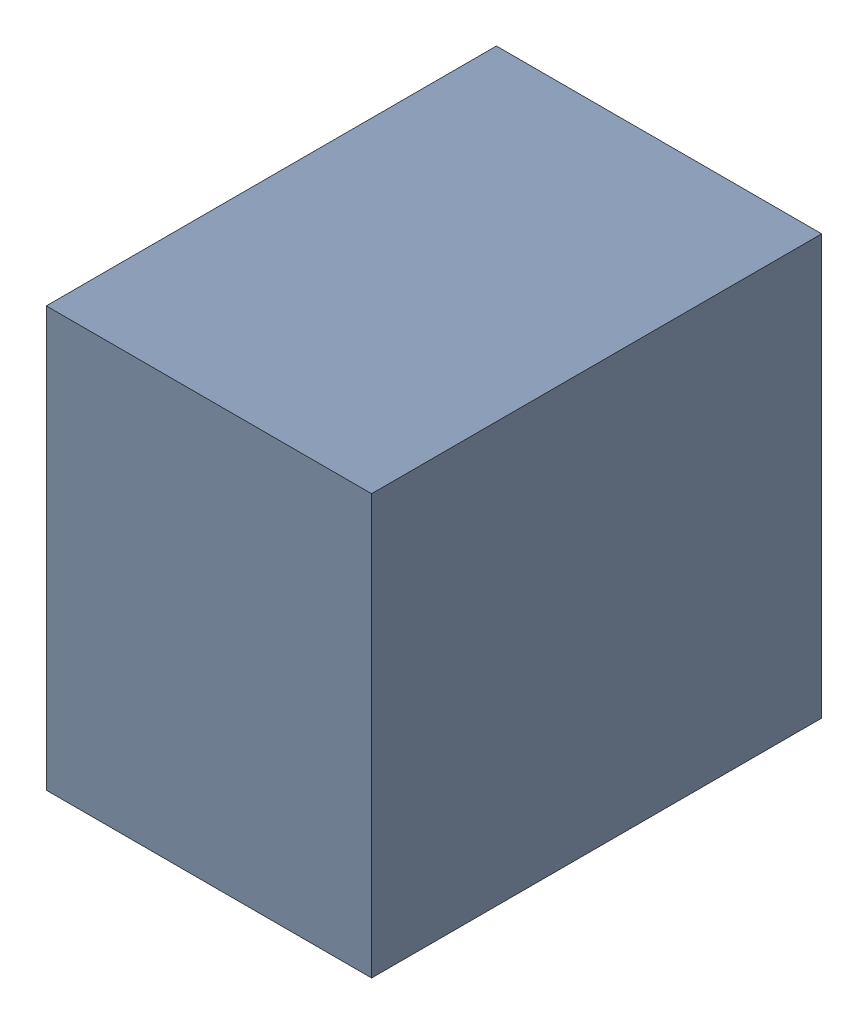
SolidWorks assembly R317_1PCB, configuration Default. Lengths in mm.
Overall size (3.18 4.1 4.4).
2 component instances, 1 part files, 0 mates.
Components (placement in the parent):
- 846485736-1: 846485736 [Default] at (123.7342 109.15 0) size (3.18 4.1 4.4)
  - Extruded_41-1: Extruded_41 [Default] at origin size (3.18 4.1 4.4)
